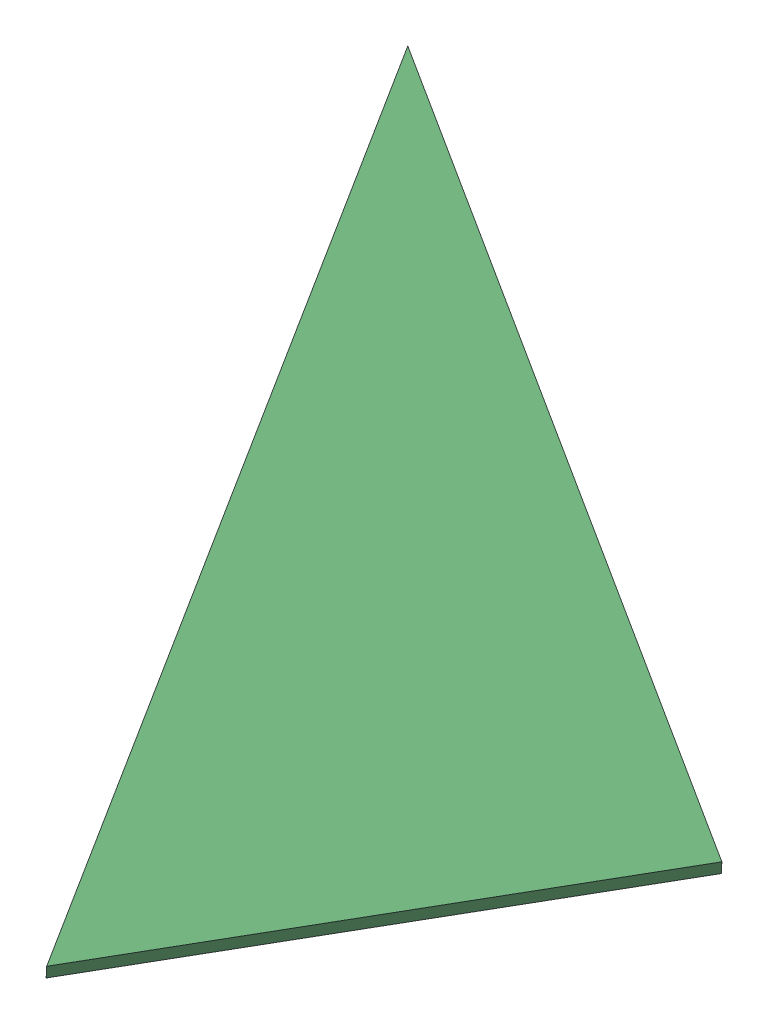
SolidWorks assembly GE-16141_ASM, configuration Default. Lengths in mm.
Overall size (1108.93 147.32 959.36).
3 component instances, 3 part files, 0 mates.
Components (placement in the parent):
- GE-16141-02-1: GE-16141-02 [Default] at origin size (457.2 129.07 779.19)
- GE-16141-03-1: GE-16141-03 [Default] at (-17.3485 0 17.3485) x (0.5 0 -0.866025) z (0.866025 0 0.5) size (12.7 127.82 772.85)
- GE-16141-01-1: GE-16141-01 [Default] at (-11.1261 147.3189 6.2764) x (-0.5 0 0.866025) z (0.857615 -0.13903 0.495144) size (552.73 12.7 969.01)
